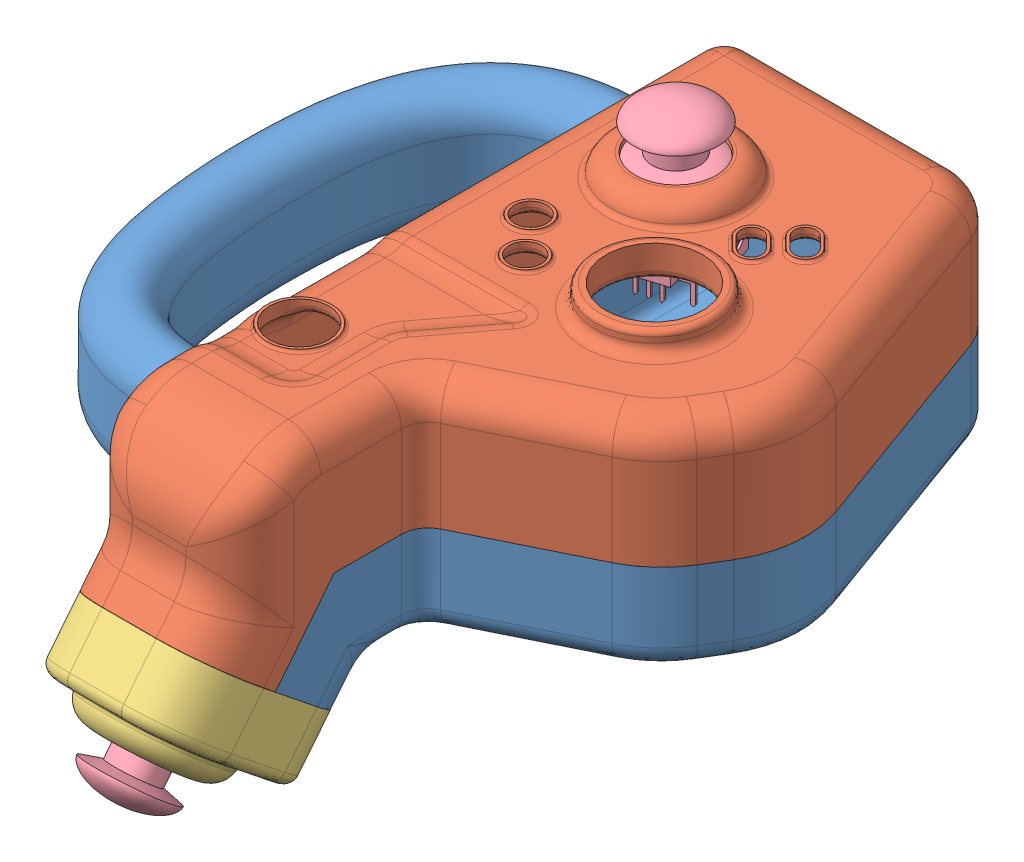
SolidWorks assembly OHGC_assembly, configuration Default. Lengths in mm.
Overall size (136.48 96.01 175.15).
5 component instances, 4 part files, 11 mates.
Components (placement in the parent):
- OHGC_back-1: OHGC_back [Default] at (-20.0195 -13.4368 22.9284) size (136.48 48.24 144.3)
- OHGC_front-1: OHGC_front [Default] at (-20.0195 -13.4368 22.9284) size (87.4 51.64 159.47)
- OHGC_bottom-1: OHGC_bottom [Default] at (-20.0195 -14.025 23.3989) size (40.3 36.13 40.62)
- 9032-1: 9032 [Default] at (16.5625 22.8112 -28.9527) x (-0.292474 0 -0.956274) z (0 1 0) size (26.67 27.62 34.67)
- 9032-3: 9032 [Default] at (-10.8024 -5.6709 75.0724) x (0.278302 -0.600016 -0.75002) z (0 -0.780869 0.624695) size (26.67 27.62 34.67)
Mates (geometry in assembly coordinates):
- Parallel3: parallel anti-aligned: line of OHGC_back-1 through (-18.7495 -8.2291 70.9838) axis (0 0.780869 -0.624695); line of OHGC_front-1 through (-18.7495 8.1532 57.8534) axis (0 -0.780869 0.624695)
- Coincident12: coincident anti-aligned: plane of OHGC_back-1 through (-18.7495 8.1532 -45.6516) normal (-1 0 0); plane of OHGC_front-1 through (-18.7495 9.4232 -65.9716) normal (1 0 0)
- Coincident13: coincident anti-aligned: plane of OHGC_back-1 through (24.4305 8.1532 41.9784) normal (0 1 0); plane of OHGC_front-1 through (66.2327 8.1532 -72.3216) normal (0 -1 0)
- Coincident14: coincident anti-aligned: plane of OHGC_back-1 through (34.5851 8.1532 -71.0516) normal (0 0 -1); plane of OHGC_front-1 through (34.5851 9.4232 -71.0516) normal (0 0 1)
- Coincident15: coincident anti-aligned: plane of OHGC_back-1 through (16.8105 -7.4358 71.9755) normal (-1 0 0); plane of OHGC_bottom-1 through (16.8105 -7.0645 74.4726) normal (1 0 0)
- Coincident16: coincident anti-aligned: plane of OHGC_back-1 through (13.0005 -20.5195 55.6209) normal (0 0.624695 0.780869); plane of OHGC_bottom-1 through (13.0005 -21.5112 56.4143) normal (0 -0.624695 -0.780869)
- Coincident17: coincident anti-aligned: plane of OHGC_back-1 through (66.2327 -8.4275 72.7689) normal (0 -0.780869 0.624695); plane of OHGC_bottom-1 through (-20.0195 -34.6948 39.9348) normal (0 0.780869 -0.624695)
- Concentric1: concentric aligned: circle of OHGC_front-1; cylinder of 9032-1 through (6.6505 22.2143 -34.2216) axis (0 -1 0) radius 5.588
- Tangent1: tangent: circle of OHGC_front-1; face of 9032-1
- Concentric2: concentric aligned: circle of OHGC_bottom-1; circle of 9032-3
- Tangent2: tangent: circle of OHGC_bottom-1; edge_curve of 9032-3
